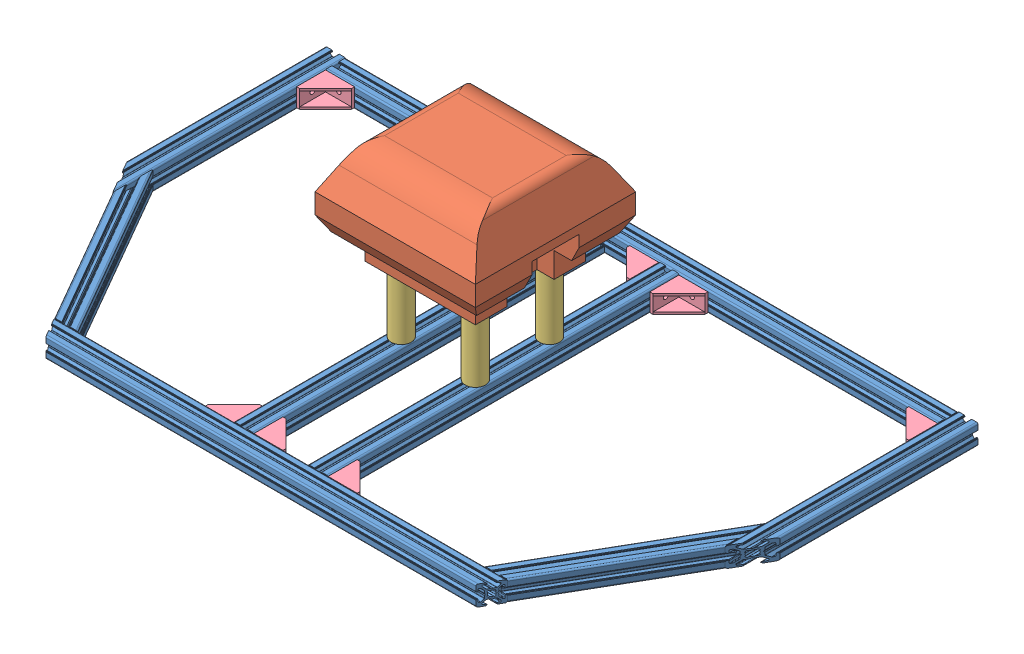
SolidWorks assembly GPS Lid Assembly, configuration Default. Lengths in mm.
Overall size (651 185.1 390).
15 component instances, 4 part files, 25 mates.
Components (placement in the parent):
- GPS Lid-1: GPS Lid [Default<As Machined>] at (264.959 312.4365 321.65) size (651 20 390)
- GPS-1: GPS [Default] at (220.0427 343.778 364.2591) size (160 165 160)
  - Electronics_GPS-1: Electronics_GPS [Default] at (45.0778 103.759 123.5701) size (160 100 160)
  - GPS_Spacer-1: GPS_Spacer [Default] at (82.0778 -21.241 160.5701) x (-0.327705 0 -0.94478) z (0 1 0) size (20 20 65)
  - GPS_Spacer-2: GPS_Spacer [Default] at (8.0778 -21.241 86.5701) x (0.991067 0 0.133362) z (0 1 0) size (20 20 65)
  - GPS_Spacer-3: GPS_Spacer [Default] at (8.0778 -21.241 160.5701) x (0.953346 0 0.301881) z (0 1 0) size (20 20 65)
  - GPS_Spacer-4: GPS_Spacer [Default] at (82.0778 -21.241 86.5701) x (0.550145 0 -0.835069) z (0 1 0) size (20 20 65)
- L- Bracket-1: L- Bracket [Default] at (217.9605 311.9355 681.6515) x (0 -1 0) z (1 0 0) size (18 29 29)
- L- Bracket-2: L- Bracket [Default] at (237.9592 312.9376 681.6515) x (0 1 0) z (-1 0 0) size (18 29 29)
- L- Bracket-3: L- Bracket [Default] at (311.9592 312.9376 681.6515) x (0 1 0) z (-1 0 0) size (18 29 29)
- L- Bracket-4: L- Bracket [Default] at (-40.5408 312.9376 331.6485) x (0 -1 0) z (-1 0 0) size (18 29 29)
- L- Bracket-5: L- Bracket [Default] at (570.4605 312.9376 331.6485) x (0 1 0) z (1 0 0) size (18 29 29)
- L- Bracket-6: L- Bracket [Default] at (311.9592 311.9355 331.6485) x (0 -1 0) z (-1 0 0) size (18 29 29)
- L- Bracket-7: L- Bracket [Default] at (291.9605 312.9376 331.6485) x (0 1 0) z (1 0 0) size (18 29 29)
- L- Bracket-8: L- Bracket [Default] at (217.9605 312.9376 331.6485) x (0 1 0) z (1 0 0) size (18 29 29)
Mates (geometry in assembly coordinates):
- Lock1: lock: unknown of GPS Lid-1; unknown of GPS-1/Electronics_GPS-1
- Coincident1: coincident: plane of assembly; plane of assembly; plane of GPS Lid-1 through (217.9605 320.9355 691.65) normal (-1 0 0); plane of L- Bracket-1 through (217.9605 320.9355 652.6515) normal (1 0 0)
- Coincident2: coincident: plane of assembly; plane of assembly; plane of GPS Lid-1 through (56.2688 308.6876 681.6515) normal (0 0 -1); plane of L- Bracket-1 through (217.9605 320.9355 681.6515) normal (0 0 1)
- Coincident3: coincident: line of assembly; line of assembly; line of GPS Lid-1 through (217.9605 320.9355 681.6515) axis (0 0 -1); line of L- Bracket-1 through (217.9605 320.9355 652.6515) axis (0 0 1)
- Coincident4: coincident: plane of assembly; plane of assembly; plane of GPS Lid-1 through (56.2688 320.9355 681.6515) normal (0 0 -1); plane of L- Bracket-2 through (237.9592 303.9376 681.6515) normal (0 0 1)
- Coincident5: coincident: plane of assembly; plane of assembly; plane of GPS Lid-1 through (237.9592 316.1855 691.65) normal (1 0 0); plane of L- Bracket-2 through (237.9592 303.9376 652.6515) normal (-1 0 0)
- Coincident6: coincident: line of assembly; line of assembly; line of GPS Lid-1 through (38.9509 303.9376 681.6515) axis (1 0 0); line of L- Bracket-2 through (237.9592 303.9376 681.6515) axis (1 0 0)
- Coincident7: coincident: plane of assembly; plane of assembly; plane of GPS Lid-1 through (311.9592 303.9376 691.65) normal (1 0 0); plane of L- Bracket-3 through (311.9592 303.9376 652.6515) normal (-1 0 0)
- Coincident8: coincident: plane of assembly; plane of assembly; plane of GPS Lid-1 through (56.2688 308.6876 681.6515) normal (0 0 -1); plane of L- Bracket-3 through (311.9592 303.9376 681.6515) normal (0 0 1)
- Coincident9: coincident: line of assembly; line of assembly; line of GPS Lid-1 through (38.9509 303.9376 681.6515) axis (1 0 0); line of L- Bracket-3 through (311.9592 303.9376 681.6515) axis (1 0 0)
- Coincident10: coincident: plane of assembly; plane of assembly; plane of GPS Lid-1 through (-40.5408 303.9376 506.65) normal (1 0 0); plane of L- Bracket-4 through (-40.5408 321.9376 360.6485) normal (-1 0 0)
- Coincident11: coincident: plane of assembly; plane of assembly; plane of GPS Lid-1 through (580.459 308.6876 331.6485) normal (0 0 1); plane of L- Bracket-4 through (-40.5408 321.9376 331.6485) normal (0 0 -1)
- Coincident12: coincident: line of assembly; line of assembly; line of GPS Lid-1 through (-40.5408 303.9376 543.9678) axis (0 0 -1); line of L- Bracket-4 through (-40.5408 303.9376 360.6485) axis (0 0 -1)
- Coincident13: coincident: plane of assembly; plane of assembly; plane of GPS Lid-1 through (580.459 320.9355 331.6485) normal (0 0 1); plane of L- Bracket-5 through (570.4605 303.9376 331.6485) normal (0 0 -1)
- Coincident14: coincident: plane of assembly; plane of assembly; plane of GPS Lid-1 through (570.4605 308.6876 506.65) normal (-1 0 0); plane of L- Bracket-5 through (570.4605 303.9376 360.6485) normal (1 0 0)
- Coincident15: coincident: line of assembly; line of assembly; line of GPS Lid-1 through (570.4605 303.9376 331.6485) axis (-1 0 0); line of L- Bracket-5 through (570.4605 303.9376 331.6485) axis (-1 0 0)
- Coincident16: coincident: plane of assembly; plane of assembly; plane of GPS Lid-1 through (311.9592 303.9376 691.65) normal (1 0 0); plane of L- Bracket-6 through (311.9592 320.9355 360.6485) normal (-1 0 0)
- Coincident17: coincident: plane of assembly; plane of assembly; plane of GPS Lid-1 through (580.459 308.6876 331.6485) normal (0 0 1); plane of L- Bracket-6 through (311.9592 320.9355 331.6485) normal (0 0 -1)
- Coincident18: coincident: line of assembly; line of assembly; line of GPS Lid-1 through (570.4605 320.9355 331.6485) axis (-1 0 0); line of L- Bracket-6 through (311.9592 320.9355 331.6485) axis (1 0 0)
- Coincident19: coincident: plane of assembly; plane of assembly; plane of GPS Lid-1 through (580.459 320.9355 331.6485) normal (0 0 1); plane of L- Bracket-7 through (291.9605 303.9376 331.6485) normal (0 0 -1)
- Coincident20: coincident: plane of assembly; plane of assembly; plane of GPS Lid-1 through (291.9605 308.6876 691.65) normal (-1 0 0); plane of L- Bracket-7 through (291.9605 303.9376 360.6485) normal (1 0 0)
- Coincident21: coincident: line of assembly; line of assembly; line of GPS Lid-1 through (570.4605 303.9376 331.6485) axis (-1 0 0); line of L- Bracket-7 through (291.9605 303.9376 331.6485) axis (-1 0 0)
- Coincident22: coincident: plane of assembly; plane of assembly; plane of GPS Lid-1 through (217.9605 308.6876 691.65) normal (-1 0 0); plane of L- Bracket-8 through (217.9605 303.9376 360.6485) normal (1 0 0)
- Coincident23: coincident: plane of assembly; plane of assembly; plane of GPS Lid-1 through (580.459 308.6876 331.6485) normal (0 0 1); plane of L- Bracket-8 through (217.9605 303.9376 331.6485) normal (0 0 -1)
- Coincident24: coincident: line of assembly; line of assembly; line of GPS Lid-1 through (570.4605 303.9376 331.6485) axis (-1 0 0); line of L- Bracket-8 through (217.9605 303.9376 331.6485) axis (-1 0 0)
